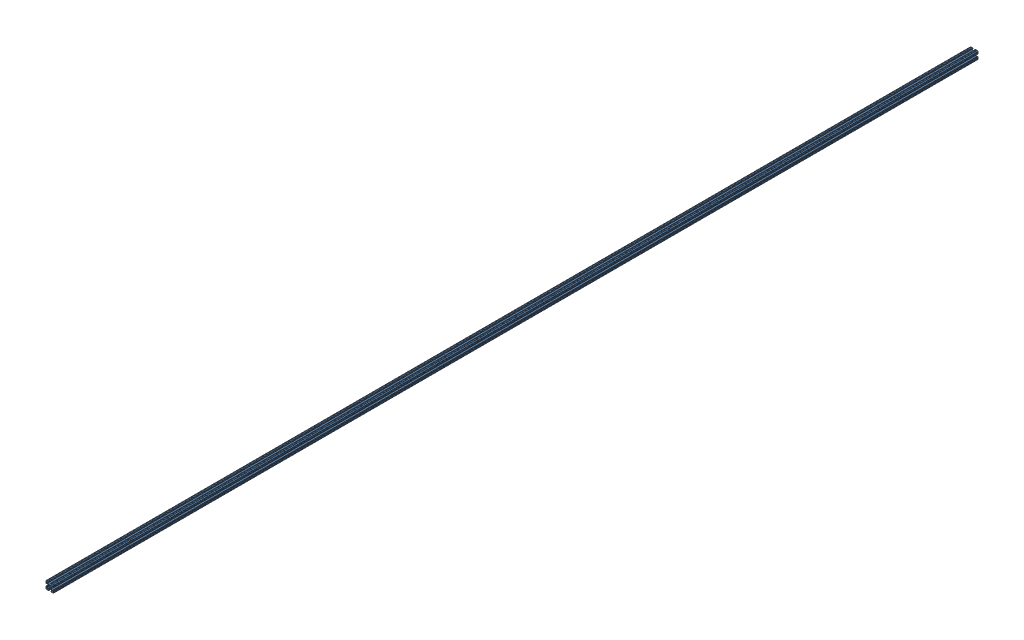
SolidWorks assembly Assem1, configuration Default. Lengths in mm.
Overall size (25.4 25.4 3048).
24 component instances, 1 part files, 69 mates.
Components (placement in the parent):
- connector_rod-1: connector_rod [Default] at (118.4239 27.3588 26.3342) size (25.4 25.4 127)
- connector_rod-2: connector_rod [Default] at (118.4239 27.3588 -100.6658) size (25.4 25.4 127)
- connector_rod-3: connector_rod [Default] at (118.4239 27.3588 -227.6658) size (25.4 25.4 127)
- connector_rod-4: connector_rod [Default] at (118.4239 27.3588 -354.6658) size (25.4 25.4 127)
- connector_rod-5: connector_rod [Default] at (118.4239 27.3588 153.3342) size (25.4 25.4 127)
- connector_rod-6: connector_rod [Default] at (118.4239 27.3588 280.3342) size (25.4 25.4 127)
- connector_rod-7: connector_rod [Default] at (118.4239 27.3588 407.3342) size (25.4 25.4 127)
- connector_rod-8: connector_rod [Default] at (118.4239 27.3588 -481.6658) size (25.4 25.4 127)
- connector_rod-9: connector_rod [Default] at (118.4239 27.3588 -608.6658) size (25.4 25.4 127)
- connector_rod-10: connector_rod [Default] at (118.4239 27.3588 -862.6658) size (25.4 25.4 127)
- connector_rod-11: connector_rod [Default] at (118.4239 27.3588 -735.6658) size (25.4 25.4 127)
- connector_rod-12: connector_rod [Default] at (118.4239 27.3588 788.3342) size (25.4 25.4 127)
- connector_rod-13: connector_rod [Default] at (118.4239 27.3588 534.3342) size (25.4 25.4 127)
- connector_rod-14: connector_rod [Default] at (118.4239 27.3588 915.3342) x (-1 0 0) z (0 0 -1) size (25.4 25.4 127)
- connector_rod-15: connector_rod [Default] at (118.4239 27.3588 915.3342) size (25.4 25.4 127)
- connector_rod-16: connector_rod [Default] at (118.4239 27.3588 661.3342) size (25.4 25.4 127)
- connector_rod-17: connector_rod [Default] at (118.4239 27.3588 1042.3342) x (-1 0 0) z (0 0 -1) size (25.4 25.4 127)
- connector_rod-18: connector_rod [Default] at (118.4239 27.3588 1296.3342) size (25.4 25.4 127)
- connector_rod-19: connector_rod [Default] at (118.4239 27.3588 -1116.6658) x (-1 0 0) z (0 0 -1) size (25.4 25.4 127)
- connector_rod-20: connector_rod [Default] at (118.4239 27.3588 -1370.6658) x (-1 0 0) z (0 0 -1) size (25.4 25.4 127)
- connector_rod-21: connector_rod [Default] at (118.4239 27.3588 1296.3342) x (-1 0 0) z (0 0 -1) size (25.4 25.4 127)
- connector_rod-22: connector_rod [Default] at (118.4239 27.3588 -1243.6658) x (-1 0 0) z (0 0 -1) size (25.4 25.4 127)
- connector_rod-23: connector_rod [Default] at (118.4239 27.3588 1423.3342) x (-1 0 0) z (0 0 -1) size (25.4 25.4 127)
- connector_rod-24: connector_rod [Default] at (118.4239 27.3588 1550.3342) x (-1 0 0) z (0 0 -1) size (25.4 25.4 127)
Mates (geometry in assembly coordinates):
- Coincident1: coincident anti-aligned: plane of connector_rod-1 through (105.7239 17.3004 -100.6658) normal (0 0 -1); plane of connector_rod-2 through (105.7239 17.3004 -100.6658) normal (0 0 1)
- Coincident2: coincident aligned: plane of connector_rod-1 through (127.9743 40.0588 -100.6658) normal (0 1 0); plane of connector_rod-2 through (127.9743 40.0588 -227.6658) normal (0 1 0)
- Coincident3: coincident aligned: plane of connector_rod-1 through (131.1239 17.8084 -100.6658) normal (1 0 0); plane of connector_rod-2 through (131.1239 17.8084 -227.6658) normal (1 0 0)
- Coincident4: coincident anti-aligned: plane of connector_rod-2 through (105.7239 17.3004 -227.6658) normal (0 0 -1); plane of connector_rod-3 through (105.7239 17.3004 -227.6658) normal (0 0 1)
- Coincident5: coincident aligned: plane of connector_rod-2 through (127.9743 40.0588 -227.6658) normal (0 1 0); plane of connector_rod-3 through (127.9743 40.0588 -354.6658) normal (0 1 0)
- Coincident6: coincident aligned: plane of connector_rod-2 through (131.1239 33.6919 -227.6658) normal (1 0 0); plane of connector_rod-3 through (131.1239 33.6919 -354.6658) normal (1 0 0)
- Coincident7: coincident anti-aligned: plane of connector_rod-3 through (105.7239 17.3004 -354.6658) normal (0 0 -1); plane of connector_rod-4 through (105.7239 17.3004 -354.6658) normal (0 0 1)
- Coincident8: coincident aligned: plane of connector_rod-3 through (127.9743 40.0588 -354.6658) normal (0 1 0); plane of connector_rod-4 through (127.9743 40.0588 -481.6658) normal (0 1 0)
- Coincident9: coincident aligned: plane of connector_rod-3 through (131.1239 17.8084 -354.6658) normal (1 0 0); plane of connector_rod-4 through (131.1239 17.8084 -481.6658) normal (1 0 0)
- Coincident10: coincident anti-aligned: plane of connector_rod-1 through (105.7239 17.3004 26.3342) normal (0 0 1); plane of connector_rod-5 through (105.7239 17.3004 26.3342) normal (0 0 -1)
- Coincident11: coincident aligned: plane of connector_rod-1 through (112.0908 40.0588 -100.6658) normal (0 1 0); plane of connector_rod-5 through (112.0908 40.0588 26.3342) normal (0 1 0)
- Coincident12: coincident aligned: plane of connector_rod-1 through (105.7239 36.9092 -100.6658) normal (-1 0 0); plane of connector_rod-5 through (105.7239 36.9092 26.3342) normal (-1 0 0)
- Coincident13: coincident anti-aligned: plane of connector_rod-5 through (105.7239 17.3004 153.3342) normal (0 0 1); plane of connector_rod-6 through (105.7239 17.3004 153.3342) normal (0 0 -1)
- Coincident14: coincident aligned: plane of connector_rod-5 through (112.0908 40.0588 26.3342) normal (0 1 0); plane of connector_rod-6 through (112.0908 40.0588 153.3342) normal (0 1 0)
- Coincident15: coincident aligned: plane of connector_rod-5 through (131.1239 33.6919 26.3342) normal (1 0 0); plane of connector_rod-6 through (131.1239 33.6919 153.3342) normal (1 0 0)
- Coincident16: coincident anti-aligned: plane of connector_rod-6 through (105.7239 17.3004 280.3342) normal (0 0 1); plane of connector_rod-7 through (105.7239 17.3004 280.3342) normal (0 0 -1)
- Coincident17: coincident aligned: plane of connector_rod-6 through (112.0908 40.0588 153.3342) normal (0 1 0); plane of connector_rod-7 through (112.0908 40.0588 280.3342) normal (0 1 0)
- Coincident18: coincident aligned: plane of connector_rod-6 through (105.7239 36.9092 153.3342) normal (-1 0 0); plane of connector_rod-7 through (105.7239 36.9092 280.3342) normal (-1 0 0)
- Coincident19: coincident anti-aligned: plane of connector_rod-4 through (105.7239 17.3004 -481.6658) normal (0 0 -1); plane of connector_rod-8 through (105.7239 17.3004 -481.6658) normal (0 0 1)
- Coincident21: coincident aligned: plane of connector_rod-4 through (131.1239 33.6919 -481.6658) normal (1 0 0); plane of connector_rod-8 through (131.1239 33.6919 -608.6658) normal (1 0 0)
- Coincident22: coincident aligned: plane of connector_rod-4 through (124.757 14.6588 -481.6658) normal (0 -1 0); plane of connector_rod-8 through (124.757 14.6588 -608.6658) normal (0 -1 0)
- Coincident23: coincident anti-aligned: plane of connector_rod-8 through (105.7239 17.3004 -608.6658) normal (0 0 -1); plane of connector_rod-9 through (105.7239 17.3004 -608.6658) normal (0 0 1)
- Coincident24: coincident aligned: plane of connector_rod-8 through (131.1239 33.6919 -608.6658) normal (1 0 0); plane of connector_rod-9 through (131.1239 33.6919 -735.6658) normal (1 0 0)
- Coincident25: coincident aligned: plane of connector_rod-8 through (127.9743 40.0588 -608.6658) normal (0 1 0); plane of connector_rod-9 through (127.9743 40.0588 -735.6658) normal (0 1 0)
- Coincident26: coincident anti-aligned: plane of connector_rod-9 through (105.7239 17.3004 -735.6658) normal (0 0 -1); plane of connector_rod-11 through (105.7239 17.3004 -735.6658) normal (0 0 1)
- Coincident27: coincident aligned: plane of connector_rod-9 through (127.9743 40.0588 -735.6658) normal (0 1 0); plane of connector_rod-11 through (127.9743 40.0588 -862.6658) normal (0 1 0)
- Coincident28: coincident aligned: plane of connector_rod-9 through (131.1239 33.6919 -735.6658) normal (1 0 0); plane of connector_rod-11 through (131.1239 33.6919 -862.6658) normal (1 0 0)
- Coincident30: coincident anti-aligned: plane of connector_rod-10 through (105.7239 17.3004 -862.6658) normal (0 0 1); plane of connector_rod-11 through (105.7239 17.3004 -862.6658) normal (0 0 -1)
- Coincident31: coincident aligned: plane of connector_rod-10 through (127.9743 40.0588 -989.6658) normal (0 1 0); plane of connector_rod-11 through (127.9743 40.0588 -862.6658) normal (0 1 0)
- Coincident32: coincident aligned: plane of connector_rod-10 through (131.1239 33.6919 -989.6658) normal (1 0 0); plane of connector_rod-11 through (131.1239 33.6919 -862.6658) normal (1 0 0)
- Coincident36: coincident anti-aligned: plane of connector_rod-7 through (105.7239 17.3004 407.3342) normal (0 0 1); plane of connector_rod-13 through (105.7239 17.3004 407.3342) normal (0 0 -1)
- Coincident37: coincident aligned: plane of connector_rod-7 through (112.0908 40.0588 280.3342) normal (0 1 0); plane of connector_rod-13 through (112.0908 40.0588 407.3342) normal (0 1 0)
- Coincident38: coincident aligned: plane of connector_rod-7 through (131.1239 33.6919 280.3342) normal (1 0 0); plane of connector_rod-13 through (131.1239 33.6919 407.3342) normal (1 0 0)
- Coincident39: coincident anti-aligned: plane of connector_rod-13 through (105.7239 17.3004 534.3342) normal (0 0 1); plane of connector_rod-16 through (105.7239 17.3004 534.3342) normal (0 0 -1)
- Coincident40: coincident aligned: plane of connector_rod-13 through (112.0908 40.0588 407.3342) normal (0 1 0); plane of connector_rod-16 through (112.0908 40.0588 534.3342) normal (0 1 0)
- Coincident41: coincident aligned: plane of connector_rod-13 through (131.1239 33.6919 407.3342) normal (1 0 0); plane of connector_rod-16 through (131.1239 33.6919 534.3342) normal (1 0 0)
- Coincident42: coincident anti-aligned: plane of connector_rod-12 through (105.7239 17.3004 661.3342) normal (0 0 -1); plane of connector_rod-16 through (105.7239 17.3004 661.3342) normal (0 0 1)
- Coincident43: coincident aligned: plane of connector_rod-12 through (112.0908 40.0588 661.3342) normal (0 1 0); plane of connector_rod-16 through (112.0908 40.0588 534.3342) normal (0 1 0)
- Coincident44: coincident aligned: plane of connector_rod-12 through (131.1239 33.6919 661.3342) normal (1 0 0); plane of connector_rod-16 through (131.1239 33.6919 534.3342) normal (1 0 0)
- Coincident45: coincident anti-aligned: plane of connector_rod-12 through (105.7239 17.3004 788.3342) normal (0 0 1); plane of connector_rod-15 through (105.7239 17.3004 788.3342) normal (0 0 -1)
- Coincident46: coincident aligned: plane of connector_rod-12 through (112.0908 40.0588 661.3342) normal (0 1 0); plane of connector_rod-15 through (112.0908 40.0588 788.3342) normal (0 1 0)
- Coincident47: coincident aligned: plane of connector_rod-12 through (131.1239 33.6919 661.3342) normal (1 0 0); plane of connector_rod-15 through (131.1239 33.6919 788.3342) normal (1 0 0)
- Coincident48: coincident: plane of connector_rod-14 through (131.1239 17.3004 915.3342) normal (0 0 -1); plane of connector_rod-15 through (105.7239 17.3004 915.3342) normal (0 0 1)
- Coincident49: coincident: plane of connector_rod-14 through (108.8735 40.0588 1042.3342) normal (0 1 0); plane of connector_rod-15 through (112.0908 40.0588 788.3342) normal (0 1 0)
- Coincident51: coincident aligned: plane of connector_rod-14 through (105.7239 33.6919 1042.3342) normal (-1 0 0); plane of connector_rod-15 through (105.7239 36.9092 788.3342) normal (-1 0 0)
- Coincident52: coincident: plane of connector_rod-14 through (131.1239 17.3004 1042.3342) normal (0 0 1); plane of connector_rod-17 through (131.1239 17.3004 1042.3342) normal (0 0 -1)
- Coincident53: coincident: plane of connector_rod-14 through (108.8735 40.0588 1042.3342) normal (0 1 0); plane of connector_rod-17 through (108.8735 40.0588 1169.3342) normal (0 1 0)
- Coincident54: coincident aligned: plane of connector_rod-14 through (105.7239 33.6919 1042.3342) normal (-1 0 0); plane of connector_rod-17 through (105.7239 33.6919 1169.3342) normal (-1 0 0)
- Coincident55: coincident: plane of connector_rod-17 through (131.1239 17.3004 1169.3342) normal (0 0 1); plane of connector_rod-18 through (105.7239 17.3004 1169.3342) normal (0 0 -1)
- Coincident56: coincident: plane of connector_rod-17 through (105.7239 33.6919 1169.3342) normal (-1 0 0); plane of connector_rod-18 through (105.7239 36.9092 1169.3342) normal (-1 0 0)
- Coincident57: coincident aligned: plane of connector_rod-17 through (112.0908 14.6588 1169.3342) normal (0 -1 0); plane of connector_rod-18 through (108.8735 14.6588 1169.3342) normal (0 -1 0)
- Coincident58: coincident: plane of connector_rod-18 through (105.7239 17.3004 1296.3342) normal (0 0 1); plane of connector_rod-21 through (131.1239 17.3004 1296.3342) normal (0 0 -1)
- Coincident59: coincident: plane of connector_rod-18 through (131.1239 17.8084 1169.3342) normal (1 0 0); plane of connector_rod-21 through (131.1239 21.0258 1423.3342) normal (1 0 0)
- Coincident60: coincident aligned: plane of connector_rod-18 through (127.9743 40.0588 1169.3342) normal (0 1 0); plane of connector_rod-21 through (124.757 40.0588 1423.3342) normal (0 1 0)
- Coincident61: coincident: plane of connector_rod-10 through (105.7239 17.3004 -989.6658) normal (0 0 -1); plane of connector_rod-19 through (131.1239 17.3004 -989.6658) normal (0 0 1)
- Coincident62: coincident: plane of connector_rod-10 through (105.7239 36.9092 -989.6658) normal (-1 0 0); plane of connector_rod-19 through (105.7239 33.6919 -989.6658) normal (-1 0 0)
- Coincident63: coincident aligned: plane of connector_rod-10 through (112.0908 40.0588 -989.6658) normal (0 1 0); plane of connector_rod-19 through (108.8735 40.0588 -989.6658) normal (0 1 0)
- Coincident64: coincident: plane of connector_rod-19 through (131.1239 17.3004 -1116.6658) normal (0 0 -1); plane of connector_rod-22 through (131.1239 17.3004 -1116.6658) normal (0 0 1)
- Coincident65: coincident: plane of connector_rod-19 through (124.757 40.0588 -989.6658) normal (0 1 0); plane of connector_rod-22 through (124.757 40.0588 -1116.6658) normal (0 1 0)
- Coincident66: coincident aligned: plane of connector_rod-19 through (105.7239 33.6919 -989.6658) normal (-1 0 0); plane of connector_rod-22 through (105.7239 33.6919 -1116.6658) normal (-1 0 0)
- Coincident67: coincident: plane of connector_rod-20 through (131.1239 17.3004 -1243.6658) normal (0 0 1); plane of connector_rod-22 through (131.1239 17.3004 -1243.6658) normal (0 0 -1)
- Coincident68: coincident: plane of connector_rod-20 through (124.757 40.0588 -1243.6658) normal (0 1 0); plane of connector_rod-22 through (124.757 40.0588 -1116.6658) normal (0 1 0)
- Coincident69: coincident aligned: plane of connector_rod-20 through (105.7239 33.6919 -1243.6658) normal (-1 0 0); plane of connector_rod-22 through (105.7239 33.6919 -1116.6658) normal (-1 0 0)
- Coincident70: coincident: plane of connector_rod-21 through (131.1239 17.3004 1423.3342) normal (0 0 1); plane of connector_rod-23 through (131.1239 17.3004 1423.3342) normal (0 0 -1)
- Coincident71: coincident: plane of connector_rod-21 through (105.7239 33.6919 1423.3342) normal (-1 0 0); plane of connector_rod-23 through (105.7239 33.6919 1550.3342) normal (-1 0 0)
- Coincident72: coincident aligned: plane of connector_rod-21 through (108.8735 40.0588 1423.3342) normal (0 1 0); plane of connector_rod-23 through (108.8735 40.0588 1550.3342) normal (0 1 0)
- Coincident73: coincident: plane of connector_rod-23 through (131.1239 17.3004 1550.3342) normal (0 0 1); plane of connector_rod-24 through (131.1239 17.3004 1550.3342) normal (0 0 -1)
- Coincident74: coincident: plane of connector_rod-23 through (105.7239 33.6919 1550.3342) normal (-1 0 0); plane of connector_rod-24 through (105.7239 33.6919 1677.3342) normal (-1 0 0)
- Coincident75: coincident aligned: plane of connector_rod-23 through (108.8735 40.0588 1550.3342) normal (0 1 0); plane of connector_rod-24 through (108.8735 40.0588 1677.3342) normal (0 1 0)
